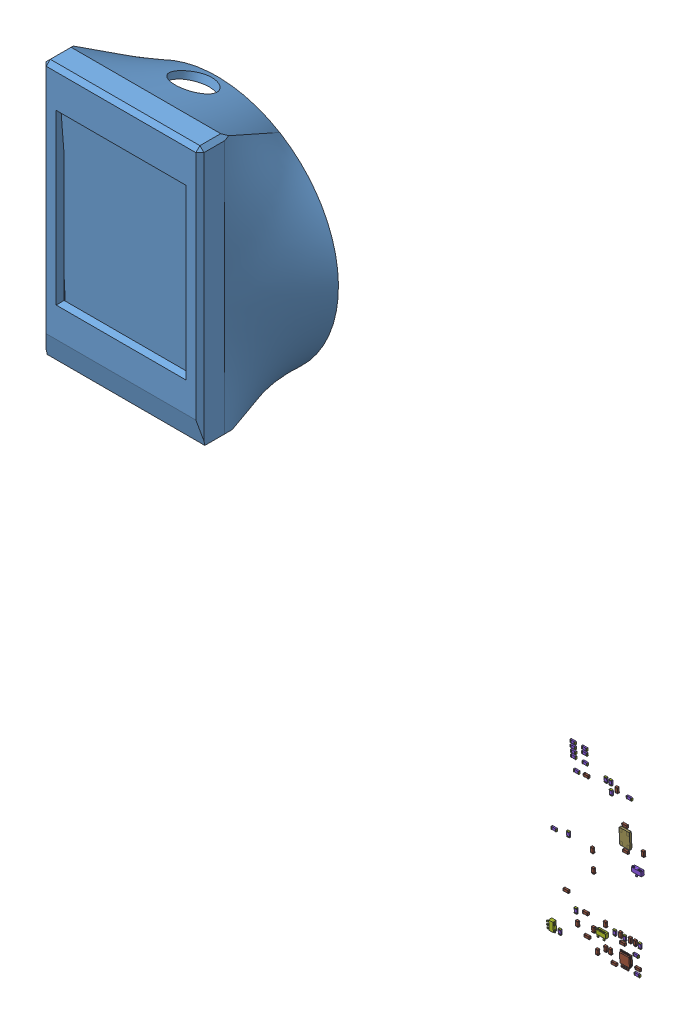
SolidWorks assembly LcdInsertGeometryTest, configuration Default. Lengths in mm.
Overall size (187.94 173.83 38.11).
202 component instances, 37 part files, 2 mates.
Components (placement in the parent):
- gen4-uLCD-24PT_simplestepmodel_R_1_0-1: gen4-uLCD-24PT_simplestepmodel_R_1_0 [Default] at (-27.6631 47.0341 93.5142) x (0.999903 0.000713 -0.013944) z (-0.013962 0.051083 -0.998597) size (171.91 172.67 8.27)
  - gen4-uLCD-24PT_simplestepmodel_R_1_0.STEP-1: gen4-uLCD-24PT_simplestepmodel_R_1_0.STEP [Default] at origin size (171.91 172.67 8.27)
    - Assembly-24PT-NoPCB.STEP-1: Assembly-24PT-NoPCB.STEP [Default] at (-2.1876 3.7664 -0.6753) size (44.92 78.36 8.27)
      - 4DLCD-24T-QVGA-LCD.STEP-1: 4DLCD-24T-QVGA-LCD.STEP [Default] at (30.7625 31.8275 58.2815) x (0 1 0) z (0 0 -1) size (60.86 43.86 8.27)
        - 4DLCD-24T-QVGA-GLASS.STEP-1: 4DLCD-24T-QVGA-GLASS.STEP [Default] at (-0.3756 -1.6155 2.7) size (60.26 42.72 1)
        - 4DLCD-24T-QVGA-METAL.STEP-1: 4DLCD-24T-QVGA-METAL.STEP [Default] at (9.2934 0 0) size (60.26 42.72 2.7)
        - 4DLCD-24T-QVGA-LCDGLASS.STEP-1: 4DLCD-24T-QVGA-LCDGLASS.STEP [Default] at (11.9434 0 2.6) size (48.96 36.72 0.1)
        - 4DLCD-24T-QVGA-FLEX.STEP-1: 4DLCD-24T-QVGA-FLEX.STEP [Default] at (-20.8366 -9.4418 -0.1) x (0 -1 0) z (-1 0 0) size (42.86 5.67 25.87)
        - 4DLCD-24T-QVGA-BASE.STEP-1: 4DLCD-24T-QVGA-BASE.STEP [Default] at (9.2934 0 0) size (58.26 40.72 2.7)
      - gen4-24-PT.STEP-1: gen4-24-PT.STEP [Default] at (24.6025 49.8444 58.3015) size (44.83 78.36 5.75)
    - Assembly-PCB-Picaso-REV1.2.STEP-1: Assembly-PCB-Picaso-REV1.2.STEP [Default] at (11.1775 28.3756 26.4775) size (165.23 149.3 2.88)
      - Gen4-PT-REV1.2-PCBComponents.STEP-1: Gen4-PT-REV1.2-PCBComponents.STEP [Default] at (33.2756 -9.2569 32.3517) x (1 0 0) z (0 0 1) size (164.21 147.75 2.22)
        - R4.STEP-1: R4.STEP [Default] at origin size (1.6 0.8 0.46)
          - User_Library-RES_0603L.STEP-1: User_Library-RES_0603L.STEP [Default] at (129.6299 152.3699 0.0127) x (-1 0 0) z (0 1 0) size (1.6 0.46 0.8)
            - User_Library-RES_0603L_RES_0603_Lead_1.STEP-1: User_Library-RES_0603L_RES_0603_Lead_1.STEP [Default] x (-1 0 0) z (0 0 -1) size (0.25 0.45 0.8)
            - User_Library-RES_0603L_RES_0603_Lead_1.STEP-2: User_Library-RES_0603L_RES_0603_Lead_1.STEP [Default] at origin size (0.25 0.45 0.8)
            - User_Library-RES_0603L_RES_0603_Body_1.STEP-1: User_Library-RES_0603L_RES_0603_Body_1.STEP [Default] at origin size (1.5 0.41 0.8)
        - R3.STEP-1: R3.STEP [Default] at origin size (0.8 1.6 0.46)
          - User_Library-RES_0603L.STEP-1: User_Library-RES_0603L.STEP [Default] at (126.2593 149.1969 0.0127) x (0 1 0) z (1 0 0) size (1.6 0.46 0.8)
            - User_Library-RES_0603L_RES_0603_Lead_1.STEP-1: User_Library-RES_0603L_RES_0603_Lead_1.STEP [Default] x (-1 0 0) z (0 0 -1) size (0.25 0.45 0.8)
            - User_Library-RES_0603L_RES_0603_Lead_1.STEP-2: User_Library-RES_0603L_RES_0603_Lead_1.STEP [Default] at origin size (0.25 0.45 0.8)
            - User_Library-RES_0603L_RES_0603_Body_1.STEP-1: User_Library-RES_0603L_RES_0603_Body_1.STEP [Default] at origin size (1.5 0.41 0.8)
        - R25.STEP-1: R25.STEP [Default] at origin size (1.6 0.8 0.46)
          - User_Library-RES_0603L.STEP-1: User_Library-RES_0603L.STEP [Default] at (129.8201 108.3301 0.0127) x (1 0 0) z (0 -1 0) size (1.6 0.46 0.8)
            - User_Library-RES_0603L_RES_0603_Lead_1.STEP-1: User_Library-RES_0603L_RES_0603_Lead_1.STEP [Default] x (-1 0 0) z (0 0 -1) size (0.25 0.45 0.8)
            - User_Library-RES_0603L_RES_0603_Lead_1.STEP-2: User_Library-RES_0603L_RES_0603_Lead_1.STEP [Default] at origin size (0.25 0.45 0.8)
            - User_Library-RES_0603L_RES_0603_Body_1.STEP-1: User_Library-RES_0603L_RES_0603_Body_1.STEP [Default] at origin size (1.5 0.41 0.8)
        - R24.STEP-1: R24.STEP [Default] at origin size (1.6 0.8 0.46)
          - User_Library-RES_0603L.STEP-1: User_Library-RES_0603L.STEP [Default] at (113.4499 109.1249 0.0127) x (-1 0 0) z (0 1 0) size (1.6 0.46 0.8)
            - User_Library-RES_0603L_RES_0603_Lead_1.STEP-1: User_Library-RES_0603L_RES_0603_Lead_1.STEP [Default] x (-1 0 0) z (0 0 -1) size (0.25 0.45 0.8)
            - User_Library-RES_0603L_RES_0603_Lead_1.STEP-2: User_Library-RES_0603L_RES_0603_Lead_1.STEP [Default] at origin size (0.25 0.45 0.8)
            - User_Library-RES_0603L_RES_0603_Body_1.STEP-1: User_Library-RES_0603L_RES_0603_Body_1.STEP [Default] at origin size (1.5 0.41 0.8)
        - R23.STEP-1: R23.STEP [Default] at origin size (0.8 1.6 0.46)
          - User_Library-RES_0603L.STEP-1: User_Library-RES_0603L.STEP [Default] at (124.125 106.8 0.0127) x (0 -1 0) z (-1 0 0) size (1.6 0.46 0.8)
            - User_Library-RES_0603L_RES_0603_Lead_1.STEP-1: User_Library-RES_0603L_RES_0603_Lead_1.STEP [Default] x (-1 0 0) z (0 0 -1) size (0.25 0.45 0.8)
            - User_Library-RES_0603L_RES_0603_Lead_1.STEP-2: User_Library-RES_0603L_RES_0603_Lead_1.STEP [Default] at origin size (0.25 0.45 0.8)
            - User_Library-RES_0603L_RES_0603_Body_1.STEP-1: User_Library-RES_0603L_RES_0603_Body_1.STEP [Default] at origin size (1.5 0.41 0.8)
        - USER_I_O.STEP-1: USER_I_O.STEP [Default] at origin size (20.5 7.15 2.05)
          - Molex-541043031-30Way-Top.STEP-1: Molex-541043031-30Way-Top.STEP [Default] at (-19.6697 44.1643 0) x (-1 0 0) z (0 1 0) size (20.5 2.05 7.15)
        - LCD.STEP-1: LCD.STEP [Default] at origin size (25.5 7.15 2.05)
          - Molex_541044031_-_Top_-_40Way.STEP-1: Molex_541044031_-_Top_-_40Way.STEP [Default] at (-14.6243 18.1077 0) x (1 0 0) z (0 -1 0) size (25.5 2.05 7.15)
        - U1.STEP-1: U1.STEP [Default] at origin size (3.1 4.94 1.1)
          - SW3dPS-MSOP8.STEP-1: SW3dPS-MSOP8.STEP [Default] at (125.8094 155.6968 1.1127) x (0 1 0) z (1 0 0) size (4.94 1.1 3.1)
        - X1.STEP-1: X1.STEP [Default] at origin size (3.2 5 0.85)
          - 628705408.STEP-1: 628705408.STEP [Default] at (127.6519 120.798 0.0127) x (0 1 0) z (0 0 1) size (5 3.2 0.85)
        - uSD1.STEP-1: uSD1.STEP [Default] at origin size (14.4 14.6 2.03)
          - 112C-TXAR-R02_C_1x.STEP-1: 112C-TXAR-R02_C_1x.STEP [Default] at (-7.7099 30.1601 0) x (-1 0 0) z (0 1 0) size (14.4 2.03 14.6)
            - 201-1.STEP-1: 201-1.STEP [Default] at origin size (13.3 1.7 13.1)
            - 301-1.STEP-1: 301-1.STEP [Default] at origin size (8.11 1.32 0.85)
            - 301_1-1.STEP-1: 301_1-1.STEP [Default] at origin size (8.11 1.32 0.85)
            - 301_2-1.STEP-1: 301_2-1.STEP [Default] at origin size (8.11 1.32 0.85)
            - 301_3-1.STEP-1: 301_3-1.STEP [Default] at origin size (8.11 1.32 0.85)
            - 301_4-1.STEP-1: 301_4-1.STEP [Default] at origin size (8.11 1.32 0.85)
            - 301_5-1.STEP-1: 301_5-1.STEP [Default] at origin size (8.11 1.32 0.85)
            - 301_6-1.STEP-1: 301_6-1.STEP [Default] at origin size (8.11 1.32 0.85)
            - 301_7-1.STEP-1: 301_7-1.STEP [Default] at origin size (8.11 1.32 0.85)
            - 401-1.STEP-1: 401-1.STEP [Default] at origin size (13.1 1.85 13.61)
            - 402_L-F-1.STEP-1: 402_L-F-1.STEP [Default] at origin size (12.65 1.73 1.45)
            - 402_R-F-1.STEP-1: 402_R-F-1.STEP [Default] at origin size (12.65 1.73 1.45)
        - U3.STEP-1: U3.STEP [Default] at origin size (2.5 3 1.1)
          - SW3DPS-SOT-23-5-DEFAULT.STEP-1: SW3DPS-SOT-23-5-DEFAULT.STEP [Default] at (102.9447 157.8103 0.5377) x (0 -1 0) z (-1 0 0) size (3 1.1 2.5)
        - U2.STEP-1: U2.STEP [Default] at origin size (3 2.5 1.1)
          - SW3DPS-SOT-23-5-DEFAULT.STEP-1: SW3DPS-SOT-23-5-DEFAULT.STEP [Default] at (118.6397 152.0697 0.5377) x (1 0 0) z (0 -1 0) size (3 1.1 2.5)
        - R22.STEP-1: R22.STEP [Default] at origin size (0.8 1.6 0.46)
          - User_Library-RES_0603L.STEP-1: User_Library-RES_0603L.STEP [Default] at (124.125 109.6 0.0127) x (0 -1 0) z (-1 0 0) size (1.6 0.46 0.8)
            - User_Library-RES_0603L_RES_0603_Lead_1.STEP-1: User_Library-RES_0603L_RES_0603_Lead_1.STEP [Default] x (-1 0 0) z (0 0 -1) size (0.25 0.45 0.8)
            - User_Library-RES_0603L_RES_0603_Lead_1.STEP-2: User_Library-RES_0603L_RES_0603_Lead_1.STEP [Default] at origin size (0.25 0.45 0.8)
            - User_Library-RES_0603L_RES_0603_Body_1.STEP-1: User_Library-RES_0603L_RES_0603_Body_1.STEP [Default] at origin size (1.5 0.41 0.8)
        - R21.STEP-1: R21.STEP [Default] at origin size (1.6 0.8 0.46)
          - User_Library-RES_0603L.STEP-1: User_Library-RES_0603L.STEP [Default] at (116.3001 105.3751 0.0127) x (1 0 0) z (0 -1 0) size (1.6 0.46 0.8)
            - User_Library-RES_0603L_RES_0603_Lead_1.STEP-1: User_Library-RES_0603L_RES_0603_Lead_1.STEP [Default] x (-1 0 0) z (0 0 -1) size (0.25 0.45 0.8)
            - User_Library-RES_0603L_RES_0603_Lead_1.STEP-2: User_Library-RES_0603L_RES_0603_Lead_1.STEP [Default] at origin size (0.25 0.45 0.8)
            - User_Library-RES_0603L_RES_0603_Body_1.STEP-1: User_Library-RES_0603L_RES_0603_Body_1.STEP [Default] at origin size (1.5 0.41 0.8)
        - R20.STEP-1: R20.STEP [Default] at origin size (0.8 1.6 0.46)
          - User_Library-RES_0603L.STEP-1: User_Library-RES_0603L.STEP [Default] at (122.6251 106.7999 0.0127) x (0 -1 0) z (-1 0 0) size (1.6 0.46 0.8)
            - User_Library-RES_0603L_RES_0603_Lead_1.STEP-1: User_Library-RES_0603L_RES_0603_Lead_1.STEP [Default] x (-1 0 0) z (0 0 -1) size (0.25 0.45 0.8)
            - User_Library-RES_0603L_RES_0603_Lead_1.STEP-2: User_Library-RES_0603L_RES_0603_Lead_1.STEP [Default] at origin size (0.25 0.45 0.8)
            - User_Library-RES_0603L_RES_0603_Body_1.STEP-1: User_Library-RES_0603L_RES_0603_Body_1.STEP [Default] at origin size (1.5 0.41 0.8)
        - R19.STEP-1: R19.STEP [Default] at origin size (1.6 0.8 0.46)
          - User_Library-RES_0603L.STEP-1: User_Library-RES_0603L.STEP [Default] at (116.3001 101.2501 0.0127) x (1 0 0) z (0 -1 0) size (1.6 0.46 0.8)
            - User_Library-RES_0603L_RES_0603_Lead_1.STEP-1: User_Library-RES_0603L_RES_0603_Lead_1.STEP [Default] x (-1 0 0) z (0 0 -1) size (0.25 0.45 0.8)
            - User_Library-RES_0603L_RES_0603_Lead_1.STEP-2: User_Library-RES_0603L_RES_0603_Lead_1.STEP [Default] at origin size (0.25 0.45 0.8)
            - User_Library-RES_0603L_RES_0603_Body_1.STEP-1: User_Library-RES_0603L_RES_0603_Body_1.STEP [Default] at origin size (1.5 0.41 0.8)
        - R18.STEP-1: R18.STEP [Default] at origin size (0.8 1.6 0.46)
          - User_Library-RES_0603L.STEP-1: User_Library-RES_0603L.STEP [Default] at (109.9251 128.3999 0.0127) x (0 -1 0) z (-1 0 0) size (1.6 0.46 0.8)
            - User_Library-RES_0603L_RES_0603_Lead_1.STEP-1: User_Library-RES_0603L_RES_0603_Lead_1.STEP [Default] x (-1 0 0) z (0 0 -1) size (0.25 0.45 0.8)
            - User_Library-RES_0603L_RES_0603_Lead_1.STEP-2: User_Library-RES_0603L_RES_0603_Lead_1.STEP [Default] at origin size (0.25 0.45 0.8)
            - User_Library-RES_0603L_RES_0603_Body_1.STEP-1: User_Library-RES_0603L_RES_0603_Body_1.STEP [Default] at origin size (1.5 0.41 0.8)
        - R17.STEP-1: R17.STEP [Default] at origin size (1.6 0.8 0.46)
          - User_Library-RES_0603L.STEP-1: User_Library-RES_0603L.STEP [Default] at (116.3001 102.6251 0.0127) x (1 0 0) z (0 -1 0) size (1.6 0.46 0.8)
            - User_Library-RES_0603L_RES_0603_Lead_1.STEP-1: User_Library-RES_0603L_RES_0603_Lead_1.STEP [Default] x (-1 0 0) z (0 0 -1) size (0.25 0.45 0.8)
            - User_Library-RES_0603L_RES_0603_Lead_1.STEP-2: User_Library-RES_0603L_RES_0603_Lead_1.STEP [Default] at origin size (0.25 0.45 0.8)
            - User_Library-RES_0603L_RES_0603_Body_1.STEP-1: User_Library-RES_0603L_RES_0603_Body_1.STEP [Default] at origin size (1.5 0.41 0.8)
        - R16.STEP-1: R16.STEP [Default] at origin size (1.6 0.8 0.46)
          - User_Library-RES_0603L.STEP-1: User_Library-RES_0603L.STEP [Default] at (112.7251 101.2501 0.0127) x (1 0 0) z (0 -1 0) size (1.6 0.46 0.8)
            - User_Library-RES_0603L_RES_0603_Lead_1.STEP-1: User_Library-RES_0603L_RES_0603_Lead_1.STEP [Default] x (-1 0 0) z (0 0 -1) size (0.25 0.45 0.8)
            - User_Library-RES_0603L_RES_0603_Lead_1.STEP-2: User_Library-RES_0603L_RES_0603_Lead_1.STEP [Default] at origin size (0.25 0.45 0.8)
            - User_Library-RES_0603L_RES_0603_Body_1.STEP-1: User_Library-RES_0603L_RES_0603_Body_1.STEP [Default] at origin size (1.5 0.41 0.8)
        - R15.STEP-1: R15.STEP [Default] at origin size (1.6 0.8 0.46)
          - User_Library-RES_0603L.STEP-1: User_Library-RES_0603L.STEP [Default] at (112.7251 102.6251 0.0127) x (1 0 0) z (0 -1 0) size (1.6 0.46 0.8)
            - User_Library-RES_0603L_RES_0603_Lead_1.STEP-1: User_Library-RES_0603L_RES_0603_Lead_1.STEP [Default] x (-1 0 0) z (0 0 -1) size (0.25 0.45 0.8)
            - User_Library-RES_0603L_RES_0603_Lead_1.STEP-2: User_Library-RES_0603L_RES_0603_Lead_1.STEP [Default] at origin size (0.25 0.45 0.8)
            - User_Library-RES_0603L_RES_0603_Body_1.STEP-1: User_Library-RES_0603L_RES_0603_Body_1.STEP [Default] at origin size (1.5 0.41 0.8)
        - R14.STEP-1: R14.STEP [Default] at origin size (1.6 0.8 0.46)
          - User_Library-RES_0603L.STEP-1: User_Library-RES_0603L.STEP [Default] at (112.7251 104.0001 0.0127) x (1 0 0) z (0 -1 0) size (1.6 0.46 0.8)
            - User_Library-RES_0603L_RES_0603_Lead_1.STEP-1: User_Library-RES_0603L_RES_0603_Lead_1.STEP [Default] x (-1 0 0) z (0 0 -1) size (0.25 0.45 0.8)
            - User_Library-RES_0603L_RES_0603_Lead_1.STEP-2: User_Library-RES_0603L_RES_0603_Lead_1.STEP [Default] at origin size (0.25 0.45 0.8)
            - User_Library-RES_0603L_RES_0603_Body_1.STEP-1: User_Library-RES_0603L_RES_0603_Body_1.STEP [Default] at origin size (1.5 0.41 0.8)
        - R13.STEP-1: R13.STEP [Default] at origin size (1.6 0.8 0.46)
          - User_Library-RES_0603L.STEP-1: User_Library-RES_0603L.STEP [Default] at (112.7001 105.3751 0.0127) x (1 0 0) z (0 -1 0) size (1.6 0.46 0.8)
            - User_Library-RES_0603L_RES_0603_Lead_1.STEP-1: User_Library-RES_0603L_RES_0603_Lead_1.STEP [Default] x (-1 0 0) z (0 0 -1) size (0.25 0.45 0.8)
            - User_Library-RES_0603L_RES_0603_Lead_1.STEP-2: User_Library-RES_0603L_RES_0603_Lead_1.STEP [Default] at origin size (0.25 0.45 0.8)
            - User_Library-RES_0603L_RES_0603_Body_1.STEP-1: User_Library-RES_0603L_RES_0603_Body_1.STEP [Default] at origin size (1.5 0.41 0.8)
        - R12.STEP-1: R12.STEP [Default] at origin size (1.6 0.8 0.46)
          - User_Library-RES_0603L.STEP-1: User_Library-RES_0603L.STEP [Default] at (105.4601 129.2201 0.0127) x (1 0 0) z (0 -1 0) size (1.6 0.46 0.8)
            - User_Library-RES_0603L_RES_0603_Lead_1.STEP-1: User_Library-RES_0603L_RES_0603_Lead_1.STEP [Default] x (-1 0 0) z (0 0 -1) size (0.25 0.45 0.8)
            - User_Library-RES_0603L_RES_0603_Lead_1.STEP-2: User_Library-RES_0603L_RES_0603_Lead_1.STEP [Default] at origin size (0.25 0.45 0.8)
            - User_Library-RES_0603L_RES_0603_Body_1.STEP-1: User_Library-RES_0603L_RES_0603_Body_1.STEP [Default] at origin size (1.5 0.41 0.8)
        - R11.STEP-1: R11.STEP [Default] at origin size (0.8 1.6 0.46)
          - User_Library-RES_0603L.STEP-1: User_Library-RES_0603L.STEP [Default] at (130.8199 149.1901 0.2277) x (0 1 0) z (1 0 0) size (1.6 0.46 0.8)
            - User_Library-RES_0603L_RES_0603_Lead_1.STEP-1: User_Library-RES_0603L_RES_0603_Lead_1.STEP [Default] x (-1 0 0) z (0 0 -1) size (0.25 0.45 0.8)
            - User_Library-RES_0603L_RES_0603_Lead_1.STEP-2: User_Library-RES_0603L_RES_0603_Lead_1.STEP [Default] at origin size (0.25 0.45 0.8)
            - User_Library-RES_0603L_RES_0603_Body_1.STEP-1: User_Library-RES_0603L_RES_0603_Body_1.STEP [Default] at origin size (1.5 0.41 0.8)
        - R10.STEP-1: R10.STEP [Default] at origin size (0.8 1.6 0.46)
          - User_Library-RES_0603L.STEP-1: User_Library-RES_0603L.STEP [Default] at (105.8251 157.7749 0.0127) x (0 -1 0) z (-1 0 0) size (1.6 0.46 0.8)
            - User_Library-RES_0603L_RES_0603_Lead_1.STEP-1: User_Library-RES_0603L_RES_0603_Lead_1.STEP [Default] x (-1 0 0) z (0 0 -1) size (0.25 0.45 0.8)
            - User_Library-RES_0603L_RES_0603_Lead_1.STEP-2: User_Library-RES_0603L_RES_0603_Lead_1.STEP [Default] at origin size (0.25 0.45 0.8)
            - User_Library-RES_0603L_RES_0603_Body_1.STEP-1: User_Library-RES_0603L_RES_0603_Body_1.STEP [Default] at origin size (1.5 0.41 0.8)
        - R6.STEP-1: R6.STEP [Default] at origin size (0.8 1.6 0.46)
          - User_Library-RES_0603L.STEP-1: User_Library-RES_0603L.STEP [Default] at (111.2301 149.1199 0.0127) x (0 -1 0) z (-1 0 0) size (1.6 0.46 0.8)
            - User_Library-RES_0603L_RES_0603_Lead_1.STEP-1: User_Library-RES_0603L_RES_0603_Lead_1.STEP [Default] x (-1 0 0) z (0 0 -1) size (0.25 0.45 0.8)
            - User_Library-RES_0603L_RES_0603_Lead_1.STEP-2: User_Library-RES_0603L_RES_0603_Lead_1.STEP [Default] at origin size (0.25 0.45 0.8)
            - User_Library-RES_0603L_RES_0603_Body_1.STEP-1: User_Library-RES_0603L_RES_0603_Body_1.STEP [Default] at origin size (1.5 0.41 0.8)
        - R2.STEP-1: R2.STEP [Default] at origin size (0.8 1.6 0.46)
          - User_Library-RES_0603L.STEP-1: User_Library-RES_0603L.STEP [Default] at (123.2095 149.2217 0.0127) x (0 -1 0) z (-1 0 0) size (1.6 0.46 0.8)
            - User_Library-RES_0603L_RES_0603_Lead_1.STEP-1: User_Library-RES_0603L_RES_0603_Lead_1.STEP [Default] x (-1 0 0) z (0 0 -1) size (0.25 0.45 0.8)
            - User_Library-RES_0603L_RES_0603_Lead_1.STEP-2: User_Library-RES_0603L_RES_0603_Lead_1.STEP [Default] at origin size (0.25 0.45 0.8)
            - User_Library-RES_0603L_RES_0603_Body_1.STEP-1: User_Library-RES_0603L_RES_0603_Body_1.STEP [Default] at origin size (1.5 0.41 0.8)
        - R1.STEP-1: R1.STEP [Default] at origin size (1.6 0.8 0.46)
          - User_Library-RES_0603L.STEP-1: User_Library-RES_0603L.STEP [Default] at (129.8093 157.6717 0.0127) x (-1 0 0) z (0 1 0) size (1.6 0.46 0.8)
            - User_Library-RES_0603L_RES_0603_Lead_1.STEP-1: User_Library-RES_0603L_RES_0603_Lead_1.STEP [Default] x (-1 0 0) z (0 0 -1) size (0.25 0.45 0.8)
            - User_Library-RES_0603L_RES_0603_Lead_1.STEP-2: User_Library-RES_0603L_RES_0603_Lead_1.STEP [Default] at origin size (0.25 0.45 0.8)
            - User_Library-RES_0603L_RES_0603_Body_1.STEP-1: User_Library-RES_0603L_RES_0603_Body_1.STEP [Default] at origin size (1.5 0.41 0.8)
        - Q1.STEP-1: Q1.STEP [Default] at origin size (3 2.5 1.1)
          - SW3DPS-SOT-23-DEFAULT.STEP-1: SW3DPS-SOT-23-DEFAULT.STEP [Default] at (130.8699 128.4699 0.5127) x (-1 0 0) z (0 1 0) size (3 1.1 2.5)
        - L1.STEP-1: L1.STEP [Default] at origin size (1.6 0.8 0.7)
          - User_Library-ECHU_PPS.STEP-1: User_Library-ECHU_PPS.STEP [Default] at (-29.8699 24.0601 0) x (1 0 0) z (0 0 1) size (1.6 0.8 0.7)
        - D1.STEP-1: D1.STEP [Default] at origin size (3.85 1.71 1.45)
          - User_Library-SOD-123_DiodesInc.STEP-1: User_Library-SOD-123_DiodesInc.STEP [Default] at (-4.125 51.69 0.5) x (-1 0 0) z (0 0 1) size (3.85 1.7 1.45)
        - C23.STEP-1: C23.STEP [Default] at origin size (1.6 0.8 0.6)
          - User_Library-cap_0603_lowprofile.STEP-1: User_Library-cap_0603_lowprofile.STEP [Default] at (114.1499 155.0999 0.0127) x (-1 0 0) z (0 0 1) size (1.6 0.8 0.6)
        - C22.STEP-1: C22.STEP [Default] at origin size (0.8 1.6 0.6)
          - User_Library-cap_0603_lowprofile.STEP-1: User_Library-cap_0603_lowprofile.STEP [Default] at (111.2301 152.9099 0.0127) x (0 -1 0) z (0 0 1) size (1.6 0.8 0.6)
        - C21.STEP-1: C21.STEP [Default] at origin size (1.6 0.8 0.6)
          - User_Library-cap_0603_lowprofile.STEP-1: User_Library-cap_0603_lowprofile.STEP [Default] at (108.1901 145.2201 0.0127) size (1.6 0.8 0.6)
        - C20.STEP-1: C20.STEP [Default] at origin size (0.8 1.6 0.6)
          - User_Library-cap_0603_lowprofile.STEP-1: User_Library-cap_0603_lowprofile.STEP [Default] at (125.7 108.25 0.0127) x (0 -1 0) z (0 0 1) size (1.6 0.8 0.6)
        - C19.STEP-1: C19.STEP [Default] at origin size (1.6 0.8 0.6)
          - User_Library-cap_0603_lowprofile.STEP-1: User_Library-cap_0603_lowprofile.STEP [Default] at (116.2251 109.1251 0.0127) size (1.6 0.8 0.6)
        - C18.STEP-1: C18.STEP [Default] at origin size (0.8 1.6 0.6)
          - User_Library-cap_0603_lowprofile.STEP-1: User_Library-cap_0603_lowprofile.STEP [Default] at (119.8094 155.6219 0.0127) x (0 1 0) z (0 0 1) size (1.6 0.8 0.6)
        - C17.STEP-1: C17.STEP [Default] at origin size (0.8 1.6 0.6)
          - User_Library-cap_0603_lowprofile.STEP-1: User_Library-cap_0603_lowprofile.STEP [Default] at (117.0499 129.4251 0.0127) x (0 1 0) z (0 0 1) size (1.6 0.8 0.6)
        - C16.STEP-1: C16.STEP [Default] at origin size (1.6 0.8 0.6)
          - User_Library-cap_0603_lowprofile.STEP-1: User_Library-cap_0603_lowprofile.STEP [Default] at (127.7501 117.2001 0.0127) size (1.6 0.8 0.6)
        - C15.STEP-1: C15.STEP [Default] at origin size (1.6 0.8 0.6)
          - User_Library-cap_0603_lowprofile.STEP-1: User_Library-cap_0603_lowprofile.STEP [Default] at (127.6749 124.4749 0.0127) x (-1 0 0) z (0 0 1) size (1.6 0.8 0.6)
        - C14.STEP-1: C14.STEP [Default] at origin size (0.8 1.6 0.6)
          - User_Library-cap_0603_lowprofile.STEP-1: User_Library-cap_0603_lowprofile.STEP [Default] at (117.0499 135.1601 0.0127) x (0 1 0) z (0 0 1) size (1.6 0.8 0.6)
        - C12.STEP-1: C12.STEP [Default] at origin size (0.8 1.6 0.6)
          - User_Library-cap_0603_lowprofile.STEP-1: User_Library-cap_0603_lowprofile.STEP [Default] at (121.2999 155.6251 0.0127) x (0 1 0) z (0 0 1) size (1.6 0.8 0.6)
        - C11.STEP-1: C11.STEP [Default] at origin size (0.8 1.6 0.6)
          - User_Library-cap_0603_lowprofile.STEP-1: User_Library-cap_0603_lowprofile.STEP [Default] at (133.1399 122.3101 0.0127) x (0 1 0) z (0 0 1) size (1.6 0.8 0.6)
        - C10.STEP-1: C10.STEP [Default] at origin size (0.8 1.6 0.6)
          - User_Library-cap_0603_lowprofile.STEP-1: User_Library-cap_0603_lowprofile.STEP [Default] at (117.1751 157.7999 0.0127) x (0 -1 0) z (0 0 1) size (1.6 0.8 0.6)
        - C9.STEP-1: C9.STEP [Default] at origin size (0.8 1.6 0.6)
          - User_Library-cap_0603_lowprofile.STEP-1: User_Library-cap_0603_lowprofile.STEP [Default] at (120.0749 148.6001 0.0127) x (0 1 0) z (0 0 1) size (1.6 0.8 0.6)
        - C8.STEP-1: C8.STEP [Default] at origin size (0.8 1.6 0.6)
          - User_Library-cap_0603_lowprofile.STEP-1: User_Library-cap_0603_lowprofile.STEP [Default] at (116.2501 152.0499 0.0127) x (0 -1 0) z (0 0 1) size (1.6 0.8 0.6)
        - C7.STEP-1: C7.STEP [Default] at origin size (1.6 0.8 0.6)
          - User_Library-cap_0603_lowprofile.STEP-1: User_Library-cap_0603_lowprofile.STEP [Default] at (113.9801 148.5501 0.0127) size (1.6 0.8 0.6)
        - C6.STEP-1: C6.STEP [Default] at origin size (1.6 0.8 0.6)
          - User_Library-cap_0603_lowprofile.STEP-1: User_Library-cap_0603_lowprofile.STEP [Default] at (125.3251 151.3251 0.0127) size (1.6 0.8 0.6)
        - C5.STEP-1: C5.STEP [Default] at origin size (1.6 0.8 0.6)
          - User_Library-cap_0603_lowprofile.STEP-1: User_Library-cap_0603_lowprofile.STEP [Default] at (129.8093 156.1967 0.0127) x (-1 0 0) z (0 0 1) size (1.6 0.8 0.6)
        - C4.STEP-1: C4.STEP [Default] at origin size (0.8 1.6 0.6)
          - User_Library-cap_0603_lowprofile.STEP-1: User_Library-cap_0603_lowprofile.STEP [Default] at (129.2845 149.1967 0.0127) x (0 -1 0) z (0 0 1) size (1.6 0.8 0.6)
        - C3.STEP-1: C3.STEP [Default] at origin size (0.8 1.6 0.6)
          - User_Library-cap_0603_lowprofile.STEP-1: User_Library-cap_0603_lowprofile.STEP [Default] at (127.7594 149.1969 0.0127) x (0 1 0) z (0 0 1) size (1.6 0.8 0.6)
        - C2.STEP-1: C2.STEP [Default] at origin size (0.8 1.6 0.6)
          - User_Library-cap_0603_lowprofile.STEP-1: User_Library-cap_0603_lowprofile.STEP [Default] at (124.7345 149.1967 0.0127) x (0 -1 0) z (0 0 1) size (1.6 0.8 0.6)
        - C1.STEP-1: C1.STEP [Default] at origin size (1.6 0.8 0.6)
          - User_Library-cap_0603_lowprofile.STEP-1: User_Library-cap_0603_lowprofile.STEP [Default] at (122.3001 158.5001 0.0127) size (1.6 0.8 0.6)
        - L4.STEP-1: L4.STEP [Default] at origin size (1.2 2 0.5)
          - 0805-Inductor.STEP-1: 0805-Inductor.STEP [Default] at (-4.7299 44.2281 0.35) x (0 1 0) z (0 0 1) size (2 1.2 0.5)
      - Gen4-PT-REV1.2OutLine.STEP-1: Gen4-PT-REV1.2OutLine.STEP [Default] at (33.2836 -9.2486 32.3147) size (31.7 42.5 0.87)
      - RoHS2.STEP-1: RoHS2.STEP [Default] at (13.5916 10.9296 32.3507) x (0.999982 -0.005956 0) z (0 0 -1) size (3.32 3.32 0.04)
      - SD-Logo.STEP-1: SD-Logo.STEP [Default] at (18.0324 18.573 32.3507) x (0.023632 -0.999721 0) z (0 0 1) size (3.32 1.09 0.04)
      - 4D-Logo.STEP-1: 4D-Logo.STEP [Default] at (11.7637 29.6556 32.3507) size (4.06 4.06 0.05)
      - Bin.STEP-1: Bin.STEP [Default] at (8.9799 11.1717 32.3507) size (1.92 2.67 0.05)
      - CE.STEP-1: CE.STEP [Default] at (17.1637 10.7288 32.3507) size (2.89 2.06 0.05)
- LcdBezel-1: LcdBezel [plane cut lid] at origin size (76.59 84.03 38.11)
Mates (geometry in assembly coordinates):
- Coincident6: coincident: circle of gen4-uLCD-24PT_simplestepmodel_R_1_0-1/gen4-uLCD-24PT_simplestepmodel_R_1_0.STEP-1/Assembly-24PT-NoPCB.STEP-1/gen4-24-PT.STEP-1; point of LcdBezel-1
- Distance3: distance = 2.286 mm aligned: plane of gen4-uLCD-24PT_simplestepmodel_R_1_0-1/gen4-uLCD-24PT_simplestepmodel_R_1_0.STEP-1/Assembly-24PT-NoPCB.STEP-1/gen4-24-PT.STEP-1 through (22.4853 41.5651 36.9578) normal (1 0 0); plane of LcdBezel-1 through (24.7713 45.4309 -64.6596) normal (1 0 0)
